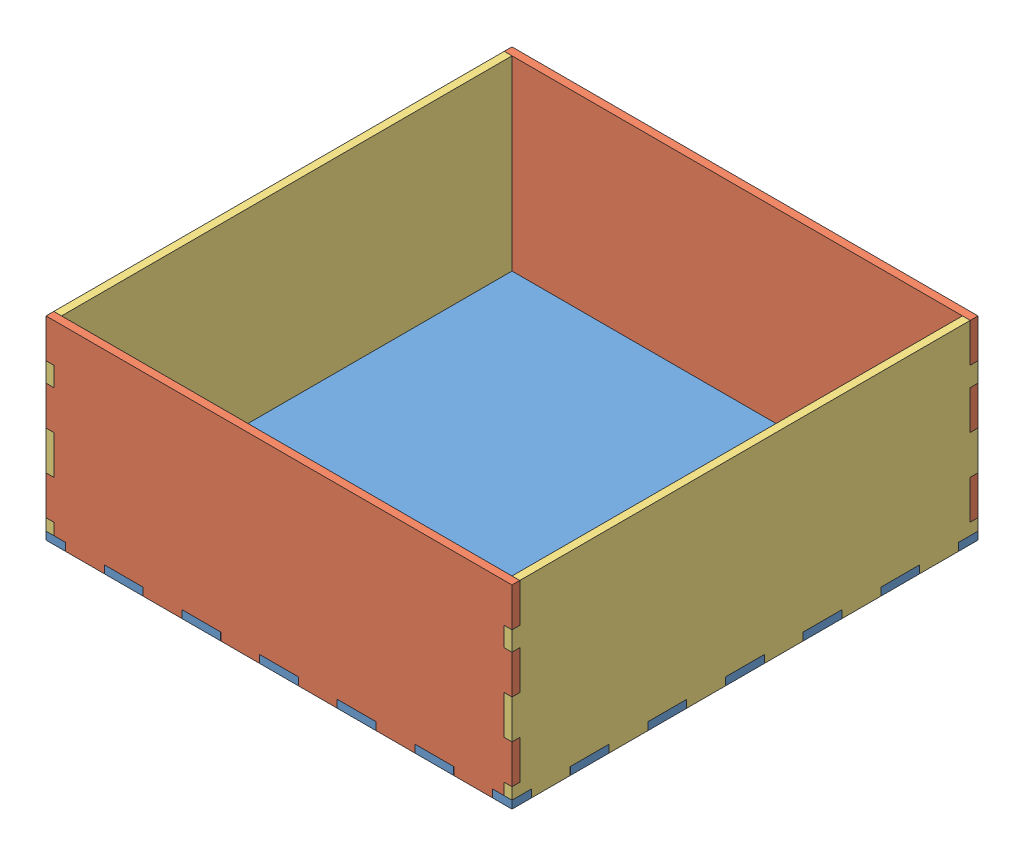
SolidWorks assembly Box_Subassembly, configuration Default. Lengths in mm.
Overall size (304.8 127 304.8).
5 component instances, 3 part files, 12 mates.
Components (placement in the parent):
- Box_Bottom-1: Box_Bottom [Default] at origin size (304.8 5.08 304.8)
- Box_Side1-1: Box_Side1 [Default] at (0 124.46 149.86) size (304.8 127 5.08)
- Box_Side1-2: Box_Side1 [Default] at (0 124.46 -149.86) size (304.8 127 5.08)
- Box_Side2-1: Box_Side2 [Default] at (149.86 124.46 0) x (0 0 -1) z (1 0 0) size (304.8 127 5.08)
- Box_Side2-2: Box_Side2 [Default] at (-149.86 124.46 0) x (0 0 -1) z (1 0 0) size (304.8 127 5.08)
Mates (geometry in assembly coordinates):
- Coincident1: coincident aligned: plane of Box_Side1-1 through (0 124.46 149.86) normal (1 0 0)
- Coincident2: coincident aligned: plane of Box_Bottom-1 through (12.7 2.54 152.4) normal (0 0 1); plane of Box_Side1-1 through (0 124.46 152.4) normal (0 0 1)
- Coincident3: coincident anti-aligned: plane of Box_Bottom-1 through (0 2.54 0) normal (0 1 0); plane of Box_Side1-1 through (0 2.54 152.4) normal (0 -1 0)
- Coincident4: coincident aligned: plane of Box_Side1-2 through (0 124.46 -149.86) normal (1 0 0)
- Coincident5: coincident aligned: plane of Box_Bottom-1 through (12.7 2.54 -152.4) normal (0 0 -1); plane of Box_Side1-2 through (0 124.46 -152.4) normal (0 0 -1)
- Coincident6: coincident aligned: plane of Box_Bottom-1 through (0 -2.54 0) normal (0 -1 0); plane of Box_Side1-2 through (0 -2.54 -147.32) normal (0 -1 0)
- Coincident7: coincident anti-aligned: plane of Box_Side2-1 through (149.86 124.46 0) normal (0 0 -1)
- Coincident8: coincident aligned: plane of Box_Bottom-1 through (0 -2.54 0) normal (0 -1 0); plane of Box_Side2-1 through (152.4 -2.54 0) normal (0 -1 0)
- Coincident9: coincident aligned: plane of Box_Bottom-1 through (152.4 2.54 -114.3) normal (1 0 0); plane of Box_Side2-1 through (152.4 124.46 0) normal (1 0 0)
- Coincident10: coincident aligned: plane of Box_Bottom-1 through (-152.4 2.54 63.5) normal (-1 0 0); plane of Box_Side2-2 through (-152.4 124.46 0) normal (-1 0 0)
- Coincident11: coincident aligned: plane of Box_Bottom-1 through (0 -2.54 0) normal (0 -1 0); plane of Box_Side2-2 through (-147.32 -2.54 0) normal (0 -1 0)
- Coincident12: coincident anti-aligned: plane of Box_Side2-2 through (-149.86 124.46 0) normal (0 0 -1)
